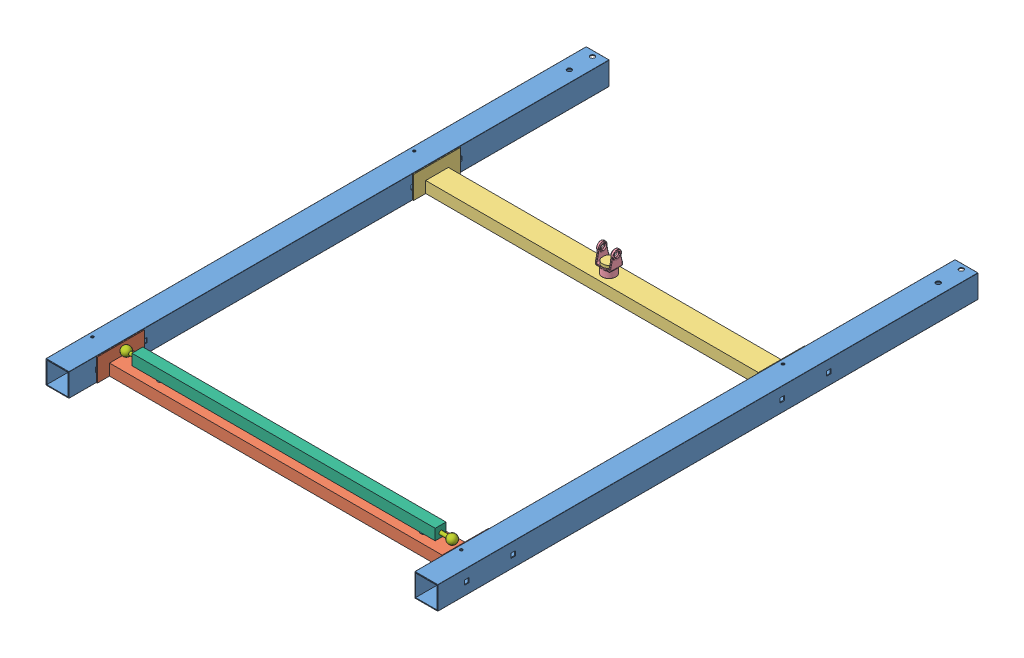
SolidWorks assembly chassis, configuration Défaut. Lengths in mm.
Overall size (866 78.98 1194).
10 component instances, 7 part files, 21 mates.
Components (placement in the parent):
- chassis_barre_laterale-1: chassis_barre_laterale [Défaut] at (-24.4445 -23.571 0) size (51 51 1194)
- chassis_barre_laterale-2: chassis_barre_laterale [Défaut] at (-839.4445 -23.571 0) size (51 51 1194)
- barre_arriere-1: barre_arriere [Défaut] at (-786.4445 -23.571 1056.3322) x (0 1 0) z (1 0 0) size (50 104 764)
- barre_centrale-1: barre_centrale [Défaut] at (-26.4445 -23.571 407.634) x (0 1 0) z (-1 0 0) size (50 104 764)
- fourche-1: fourche [Défaut] at (-406.4445 -20.721 382.634) x (0 0 1) z (-1 0 0) size (30.18 53.98 36.51)
- plot-1: plot [Défaut] at (-696.9445 1.429 1081.4017) x (0 1 0) z (0 0 1) size (10 15 15)
- plot-2: plot [Défaut] at (-115.9445 1.429 1081.4763) x (0 1 0) z (-0.196557 0 0.980492) size (10 15 15)
- barre-1: barre [Défaut] at (-746.4445 35.429 1096.7272) x (0 0 -1) z (0 -1 0) size (24 670 24)
- joint_rotule_male-1: joint_rotule_male [Défaut] at (-771.4445 21.1645 1084.3239) x (0 0.466315 -0.884619) z (1 0 0) size (20 20 35)
- joint_rotule_male-2: joint_rotule_male [Défaut] at (-51.4445 21.1645 1084.3239) x (0 0.99969 0.0249) z (-1 0 0) size (20 20 35)
Mates (geometry in assembly coordinates):
- Coïncidente1: coincident anti-aligned: plane of barre_arriere-1 through (-24.4445 -23.571 1029.3322) normal (1 0 0); plane of chassis_barre_laterale-1 through (-24.4445 -23.571 1194) normal (-1 0 0)
- Coïncidente3: coincident anti-aligned: plane of chassis_barre_laterale-1 through (-24.4445 -23.571 1194) normal (-1 0 0); plane of barre_centrale-1 through (-24.4445 26.429 434.634) normal (1 0 0)
- Parallèle1: parallel aligned: plane of chassis_barre_laterale-1 through (-24.4445 27.429 1194) normal (0 1 0); plane of barre_centrale-1 through (-786.4445 1.429 407.634) normal (0 1 0)
- Coïncidente9: coincident aligned: plane of chassis_barre_laterale-1 through (-24.4445 -23.571 1194) normal (0 -1 0); plane of barre_centrale-1 through (-786.4445 -23.571 407.634) normal (0 -1 0)
- Coïncidente10: coincident aligned: plane of chassis_barre_laterale-1 through (-24.4445 -23.571 1194) normal (0 -1 0); plane of barre_arriere-1 through (-26.4445 -23.571 1056.3322) normal (0 -1 0)
- Coïncidente11: coincident anti-aligned: plane of chassis_barre_laterale-2 through (-788.4445 -23.571 1194) normal (1 0 0); plane of barre_centrale-1 through (-788.4445 -23.571 434.634) normal (-1 0 0)
- Coïncidente12: coincident aligned: plane of chassis_barre_laterale-2 through (-839.4445 -23.571 1194) normal (0 -1 0); plane of barre_arriere-1 through (-26.4445 -23.571 1056.3322) normal (0 -1 0)
- Coïncidente13: coincident aligned: plane of chassis_barre_laterale-1 through (-24.4445 27.429 1194) normal (0 0 1); plane of chassis_barre_laterale-2 through (-839.4445 27.429 1194) normal (0 0 1)
- Coaxiale1: concentric aligned: cylinder of barre_centrale-1; cylinder of fourche-1
- Coïncidente14: coincident anti-aligned: plane of barre_centrale-1 through (-786.4445 1.429 407.634) normal (0 1 0); plane of fourche-1 through (-406.4445 1.429 382.634) normal (0 -1 0)
- Parallèle2: parallel aligned: plane of barre_centrale-1 through (-786.4445 -23.571 407.634) normal (0 0 1); plane of fourche-1 through (-419.9383 20.0536 397.7153) normal (0 0 1)
- Coïncidente15: coincident anti-aligned: plane of barre_arriere-1 through (-26.4445 1.429 1056.3322) normal (0 1 0); plane of plot-1 through (-696.9445 1.429 1081.4017) normal (0 -1 0)
- Distance1: distance = 82 mm anti-aligned: cylinder of plot-1; plane of barre_arriere-1 through (-786.4445 26.429 1029.3322) normal (1 0 0)
- Coïncidente16: coincident anti-aligned: plane of barre_arriere-1 through (-26.4445 1.429 1056.3322) normal (0 1 0); plane of plot-2 through (-115.9445 1.429 1081.4763) normal (0 -1 0)
- Distance2: distance = 82 mm anti-aligned: cylinder of plot-2; plane of barre_arriere-1 through (-26.4445 -23.571 1029.3322) normal (-1 0 0)
- Coïncidente17: coincident anti-aligned: plane of plot-2 through (-115.9445 11.429 1081.4763) normal (0 1 0); plane of barre-1 through (-76.4445 11.429 1096.7272) normal (0 -1 0)
- Parallèle3: parallel: line of barre_arriere-1; plane of barre-1 through (-746.4445 11.429 1096.7272) normal (0 0 1)
- Distance3: distance = 40 mm anti-aligned: plane of barre_arriere-1 through (-786.4445 26.429 1029.3322) normal (1 0 0); plane of barre-1 through (-746.4445 11.429 1096.7272) normal (-1 0 0)
- Coïncidente19: coincident anti-aligned: plane of barre-1 through (-746.4445 11.429 1096.7272) normal (-1 0 0); plane of joint_rotule_male-1 through (-746.4445 21.1645 1084.3239) normal (1 0 0)
- Coïncidente21: coincident anti-aligned: plane of barre-1 through (-76.4445 11.429 1096.7272) normal (1 0 0); plane of joint_rotule_male-2 through (-76.4445 21.1645 1084.3239) normal (-1 0 0)
- Coaxiale2: concentric anti-aligned: cylinder of joint_rotule_male-1; cylinder of joint_rotule_male-2
